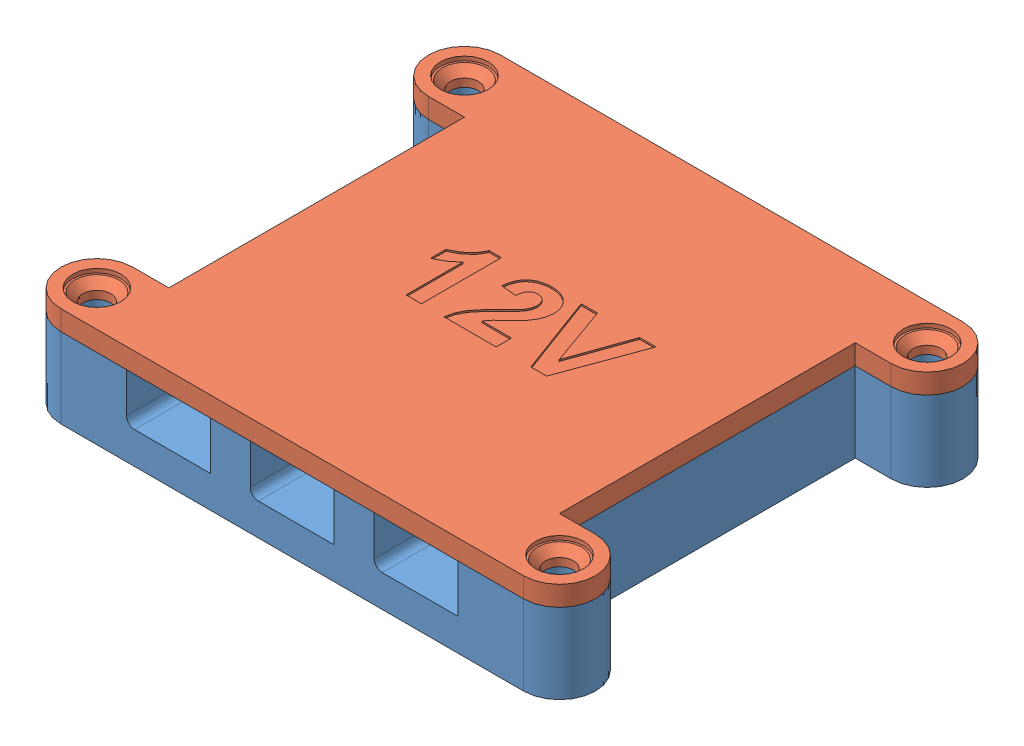
SolidWorks assembly pdb-mount, configuration Default. Lengths in mm.
Overall size (66.9 12.5 55).
2 component instances, 2 part files, 4 mates.
Components (placement in the parent):
- pdb-mount-bottom-1: pdb-mount-bottom [Default] at origin size (66.9 10 55)
- pdb-mount-top-1: pdb-mount-top [Default] at (0 10 0) x (1 0 0) z (0 1 0) size (66.9 55 2.5)
Mates (geometry in assembly coordinates):
- InPlace1: in place: plane of pdb-mount-bottom-1 through (0 6.5 0) normal (0 1 0); plane of ? through (0 6.5 0) normal (0 1 0); moOrthogonalPlaneRef_w of pdb-mount-bottom-1 through (0 6.5 0) normal (0 1 0); plane of ? through (0 6.5 0) normal (0 0 -1); plane of pdb-mount-bottom-1 through (0 6.5 0) normal (0 1 0); line of ? through (-55 0 6.5) axis (0 1 0); plane of pdb-mount-bottom-1 through (0 10 0) normal (0 1 0); unknown of pdb-mount-top-1
- Coincident1: coincident aligned: plane of pdb-mount-bottom-1; plane of pdb-mount-top-1
- Coincident2: coincident aligned: moOrthogonalPlaneRef_w of pdb-mount-bottom-1 through (0 10 0) normal (0 0 -1); plane of pdb-mount-top-1 through (0 10 0) normal (0 0 -1)
- Coincident3: coincident anti-aligned: moOrthogonalPlaneRef_w of pdb-mount-bottom-1 through (0 10 0) normal (-1 0 0); plane of pdb-mount-top-1
